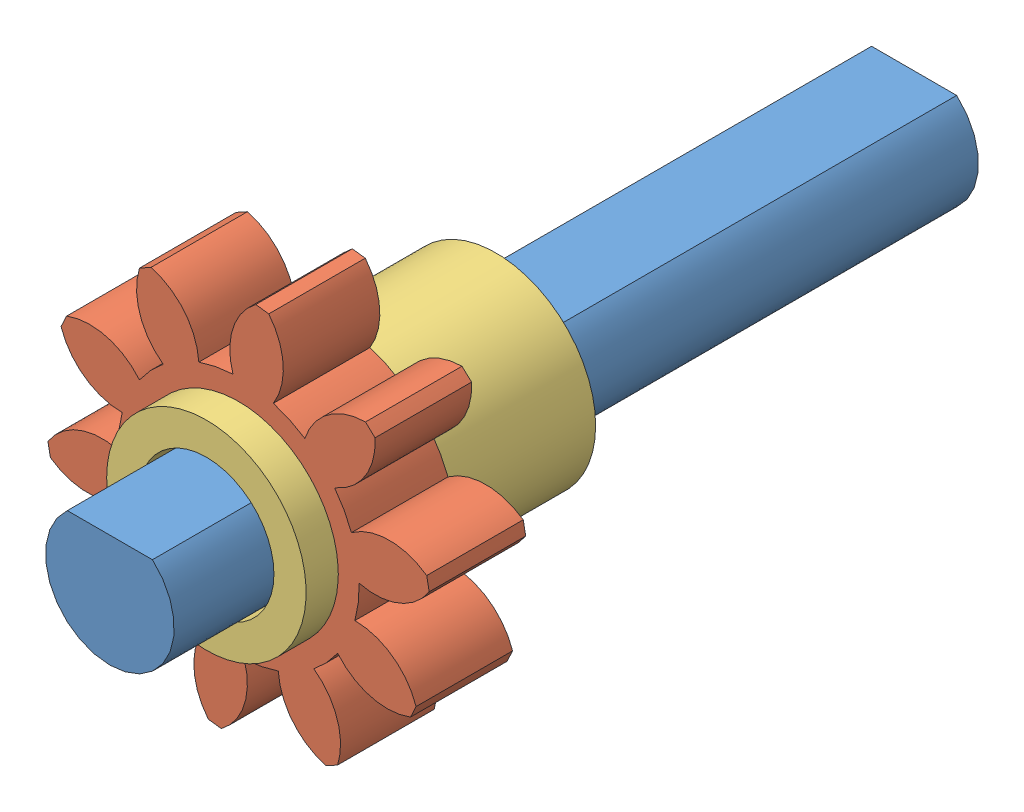
SolidWorks assembly sub 1, configuration Default. Lengths in mm.
Overall size (13.97 13.6 25).
4 component instances, 3 part files, 6 mates.
Components (placement in the parent):
- axle-1: axle [25 mm Tall] at (-2.6141 24.7144 -0.6247) size (4 3.5 25)
- root_gear-1: root_gear [10T 1.0Mod] at (-2.6141 24.7144 17.3753) x (0.981831 0.18976 0) z (0 0 1) size (12 11.53 3)
- spacer-3: spacer [1 mm Tall] at (-2.6141 24.7144 20.3753) size (6.2 6.2 1)
- spacer-4: spacer [5 mm Tall] at (-2.6141 24.7144 12.3753) size (6.2 6.2 5)
Mates (geometry in assembly coordinates):
- Coincident1: coincident anti-aligned: plane of root_gear-1 through (-2.6141 24.7144 20.3753) normal (0 0 1); plane of spacer-3 through (-2.6141 24.7144 20.3753) normal (0 0 -1)
- Coincident2: coincident anti-aligned: plane of root_gear-1 through (-2.6141 24.7144 17.3753) normal (0 0 -1); plane of spacer-4 through (-2.6141 24.7144 17.3753) normal (0 0 1)
- Concentric1: concentric aligned: cylinder of axle-1 through (-2.6141 24.7144 24.3753) axis (0 0 -1) radius 2; cylinder of spacer-3 through (-2.6141 24.7144 21.3753) axis (0 0 -1) radius 2.1
- Concentric2: concentric aligned: cylinder of axle-1 through (-2.6141 24.7144 24.3753) axis (0 0 -1) radius 2; cylinder of spacer-4 through (-2.6141 24.7144 17.3753) axis (0 0 -1) radius 2.1
- Concentric3: concentric anti-aligned: cylinder of axle-1 through (-2.6141 24.7144 24.3753) axis (0 0 -1) radius 2; cylinder of root_gear-1 through (-2.6141 24.7144 17.3753) axis (0 0 1) radius 2
- Distance1: distance = 3 mm aligned: plane of spacer-3 through (-2.6141 24.7144 21.3753) normal (0 0 1); plane of axle-1 through (-2.6141 24.7144 24.3753) normal (0 0 1)
